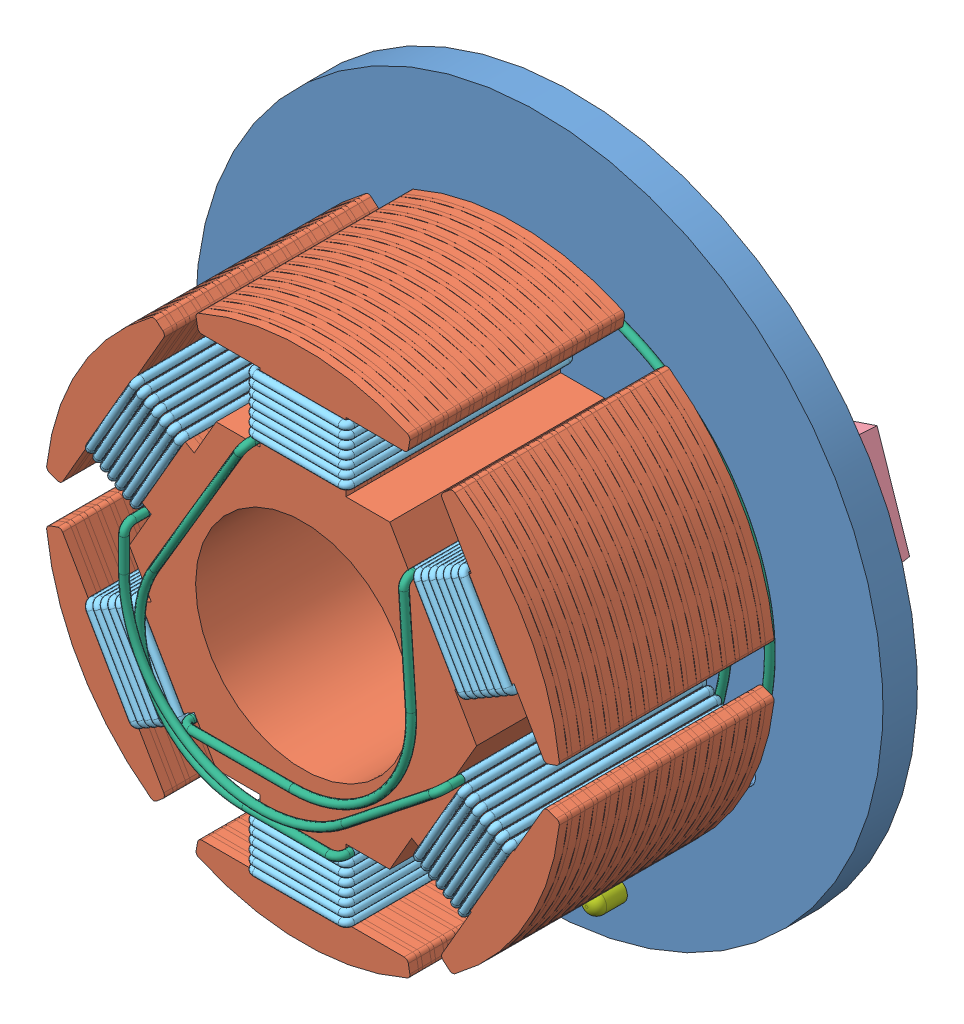
SolidWorks assembly Brushless motor, configuration Predeterminado. Lengths in mm.
Overall size (16 16 8.48).
12 component instances, 7 part files, 21 mates.
Components (placement in the parent):
- Board-1: Board [Predeterminado] at origin size (16 16 0.8)
- Stator-1: Stator [Predeterminado] at (0 0 3.55) size (11.93 12 5.5)
- Hall Effect sensor-1: Hall Effect sensor [WE] at (-5.3023 -0.9391 0) x (-0.233503 0.972356 0) z (-0.972356 -0.233503 0) size (6.3 1.6 2.6)
- Controller-1: Controller [Predeterminado] at (5.1574 2.3195 0) x (0.319288 -0.947658 0) z (0.947658 0.319288 0) size (4.81 0.99 3)
- Coil-1: Coil [Predeterminado] at (0 -5.01 1.29) x (-1 0 0) z (0 1 0) size (2.38 5.38 1.58)
- Coil-2: Coil [Predeterminado] at (-4.3388 -2.505 1.29) x (-0.5 0.866025 0) z (0.866025 0.5 0) size (2.38 5.38 1.58)
- Coil-3: Coil [Predeterminado] at (-4.3388 2.505 1.29) x (0.5 0.866025 0) z (0.866025 -0.5 0) size (2.38 5.38 1.58)
- Coil-4: Coil [Predeterminado] at (0 5.01 1.29) x (1 0 0) z (0 -1 0) size (2.38 5.38 1.58)
- Coil-5: Coil [Predeterminado] at (4.3388 2.505 1.29) x (0.5 -0.866025 0) z (-0.866025 -0.5 0) size (2.38 5.38 1.58)
- Coil-6: Coil [Predeterminado] at (4.3388 -2.505 1.29) x (-0.5 -0.866025 0) z (-0.866025 0.5 0) size (2.38 5.38 1.58)
- Pieza2^Brushless motor-1: Pieza2^Brushless motor [Predeterminado] at origin size (10.72 12.51 6.88) (virtual)
- Pieza3^Brushless motor-1: Pieza3^Brushless motor [Predeterminado] at (0 0 0.8) size (4.1 0.74 1.7) (virtual)
Mates (geometry in assembly coordinates):
- Coincidente1: coincident aligned: plane of Board-1 through (0 0 0) normal (0 0 1)
- Coincidente2: coincident aligned: plane of Board-1 through (0 0 0) normal (0 1 0)
- Coincidente3: coincident aligned: plane of Board-1 through (0 0 0) normal (1 0 0)
- Coincidente4: coincident anti-aligned: plane of Board-1 through (0 0 0.8) normal (0 0 1); plane of Stator-1 through (0 0 0.8) normal (0 0 -1)
- Concéntrica1: concentric aligned: cylinder of Board-1 through (0 0 0.8) axis (0 0 -1) radius 2.5; cylinder of Stator-1 through (0 0 6.3) axis (0 0 -1) radius 2.5
- Bloquear1: lock: unknown of Board-1; unknown of Hall Effect sensor-1
- Coincidente16: coincident anti-aligned: plane of Board-1 through (0 0 0) normal (0 0 -1); plane of Controller-1 through (5.1574 2.3195 0) normal (0 0 1)
- Bloquear2: lock: unknown of Board-1; unknown of Controller-1
- Coincidente17: coincident anti-aligned: plane of Coil-1 through (0 -5.01 1.29) normal (-1 0 0)
- Tangente1: tangent anti-aligned: plane of Stator-1 through (0 0 6.3) normal (0 0 1); cylinder of Coil-1 through (1 -5.01 6.39) axis (-1 0 0) radius 0.09
- Paralelo1: parallel aligned: plane of Coil-1 through (0 -5.01 1.29) normal (0 0 1)
- Tangente2: tangent anti-aligned: plane of Stator-1 through (2.3536 -5.1 6.1) normal (0 1 0); cylinder of Coil-1 through (1.1 -5.01 3.79) axis (0 0 1) radius 0.09
- Bloquear3: lock: unknown of Board-1; unknown of Coil-1
- EnPosición1: in place: plane of ? through (0 0 0) normal (0 0 1); moOrthogonalPlaneRef_w of ? through (0 0 0) normal (0 1 0); plane of ? through (0 0 0) normal (1 0 0); unknown of ?
- Coincidente18: coincident aligned: 
- Coincidente19: coincident aligned: plane of Pieza2^Brushless motor-1 through (0 0 0) normal (0 1 0)
- Coincidente20: coincident anti-aligned: plane of Pieza2^Brushless motor-1 through (0 0 0) normal (1 0 0)
- EnPosición2: in place: plane of ? through (0 0 0.8) normal (0 0 1); plane of Pieza3^Brushless motor-1 through (0 0 0.8) normal (0 0 1); plane of ? through (0 0 0.8) normal (0 0 1); plane of Pieza3^Brushless motor-1 through (0 0 0.8) normal (0 1 0); plane of ? through (0 0 0.8) normal (0 0 1); plane of Pieza3^Brushless motor-1 through (0 0 0.8) normal (1 0 0); plane of ? through (0 0 0.8) normal (0 0 1); unknown of Pieza3^Brushless motor-1
- Coincidente21: coincident aligned: plane of Board-1; plane of Pieza3^Brushless motor-1
- Coincidente22: coincident aligned: moOrthogonalPlaneRef_w of Board-1 through (0 0 0.8) normal (0 1 0); plane of Pieza3^Brushless motor-1 through (0 0 0.8) normal (0 1 0)
- Coincidente23: coincident anti-aligned: moOrthogonalPlaneRef_w of Board-1 through (0 0 0.8) normal (-1 0 0); plane of Pieza3^Brushless motor-1 through (0 0 0.8) normal (1 0 0)
